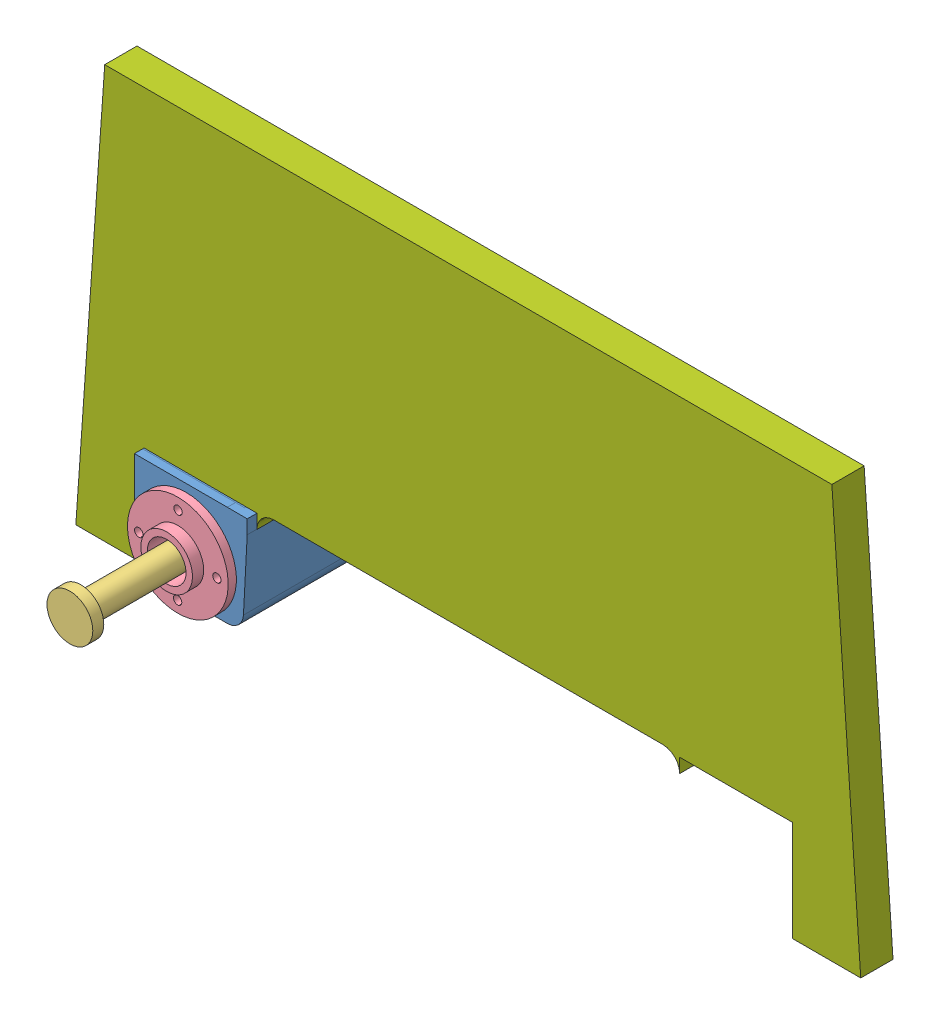
SolidWorks assembly assemblage moteur_simplifie-braquette-sol, configuration Default. Lengths in mm.
Overall size (658.2 326.23 319).
9 component instances, 8 part files, 13 mates.
Components (placement in the parent):
- Plancher simple-1: Plancher simple [Default] at (62.5689 370.838 601.9542) (suppressed, hidden)
- braquette_bleue_46.2_SLDPRT-1: braquette_bleue_46.2_SLDPRT [Default] at (-188.5719 315.838 834.4542) x (0 0 -1) z (1 0 0) size (205.75 78 138.28)
- assemblage_moteur_pla_simplifie-1: assemblage_moteur_pla_simplifie [Default] at (-199.7546 211.4142 769.8925) x (0 0 1) z (0 1 0) size (311.5 78.45 78.45)
  - moteur_pla_simplifie-2: moteur_pla_simplifie [Default] at (-156.9384 51.1827 137.4238) size (176.5 64 64)
  - moteur_axe_pla_simplifie-1: moteur_axe_pla_simplifie [Default] at (3.5616 51.1827 137.4238) size (151 35.5 35.5)
  - front_housing_moteur_pla_simplifie-2: front_housing_moteur_pla_simplifie [Default] at (64.5616 51.1827 137.4238) x (1 0 0) z (0 0.00581 0.999983) size (60 78 78)
- braquette gearbox_46.2-1: braquette gearbox_46.2 [Default] at (-173.6321 327.188 794.4741) x (-0.000012 0 -1) z (0 -1 0) size (78.5 77.86 66.5)
- braquette moteur- v2-1: braquette moteur- v2 [Default] at (-148.5686 348.838 605.4542) x (-1 0 0) z (0 0 -1) size (123.62 80 44)
- Mur_longueur_manufacturing-1: Mur_longueur_manufacturing [Default] at (62.6281 395.838 801.9542) size (658.2 320 25)
Mates (geometry in assembly coordinates):
- Coincident1: coincident anti-aligned: plane of Plancher simple-1 through (-104.0891 327.6838 376.9542) normal (-0.99863 0.052336 0); plane of braquette_bleue_46.2_SLDPRT-1 through (-101.1877 383.0446 748.6015) normal (0.99863 -0.052336 0)
- Coincident2: coincident anti-aligned: plane of Plancher simple-1 through (-266.5311 315.838 376.9542) normal (0 1 0); plane of braquette_bleue_46.2_SLDPRT-1 through (-108.5719 315.838 834.4542) normal (0 -1 0)
- Concentric1: concentric aligned: circle of braquette bleu-1; circle of assemblage_moteur_pla_simplifie-1/front_housing_moteur_pla_simplifie-2
- Parallel2: parallel anti-aligned: plane of braquette_bleue_46.2_SLDPRT-1 through (-108.5719 322.188 667.4542) normal (0 1 0); plane of assemblage_moteur_pla_simplifie-1/moteur_pla_simplifie-2 through (-127.5719 327.838 789.4542) normal (0 -1 0)
- Coincident9: coincident anti-aligned: plane of braquette_bleue_46.2_SLDPRT-1 through (-108.5719 322.188 667.4542) normal (0 1 0); plane of braquette gearbox_46.2-1 through (-173.6321 322.188 794.4741) normal (0 -1 0)
- Coincident19: coincident anti-aligned: plane of braquette_bleue_46.2_SLDPRT-1 through (-108.5719 315.838 834.4542) normal (0 0 1); plane of assemblage_moteur_pla_simplifie-1/front_housing_moteur_pla_simplifie-2 through (-148.5719 348.838 834.4542) normal (0 0 -1)
- Concentric22: concentric aligned: cylinder of assemblage_moteur_pla_simplifie-1/moteur_pla_simplifie-2 through (-148.5719 348.838 700.6742) axis (0 0 -1) radius 32; cylinder of braquette moteur- v2-1 through (-148.5719 348.838 649.4542) axis (0 0 -1) radius 33
- Distance1: distance = 7.5 mm anti-aligned: plane of assemblage_moteur_pla_simplifie-1/front_housing_moteur_pla_simplifie-2 through (-148.5719 348.838 834.4542) normal (0 0 -1); plane of Plancher simple-1 through (-116.5719 328.338 826.9542) normal (0 0 1)
- Coincident20: coincident anti-aligned: plane of Plancher simple-1 through (-266.5311 315.838 376.9542) normal (0 1 0); plane of braquette moteur- v2-1 through (-181.5719 315.838 649.4542) normal (0 -1 0)
- Distance2: distance = 7.5 mm aligned: plane of braquette moteur- v2-1 through (-148.699 346.4685 605.4542) normal (0 0 -1); plane of assemblage_moteur_pla_simplifie-1/moteur_pla_simplifie-2 through (-148.5719 348.838 612.9542) normal (0 0 -1)
- Coincident22: coincident aligned: line of Plancher simple-1 through (-116.5719 315.838 826.9542) axis (-1 0 0); line of Mur_longueur_manufacturing-1 through (-188.5719 315.838 826.9542) axis (-1 0 0)
- Parallel4: parallel aligned: plane of braquette_bleue_46.2_SLDPRT-1 through (-108.5719 315.838 834.4542) normal (0 0 1); plane of Mur_longueur_manufacturing-1 through (213.4281 382.838 826.9542) normal (0 0 1)
- Coincident25: coincident anti-aligned: plane of braquette_bleue_46.2_SLDPRT-1 through (-188.5719 315.838 834.4542) normal (-1 0 0); plane of Mur_longueur_manufacturing-1 through (-188.5719 393.838 826.9542) normal (1 0 0)
